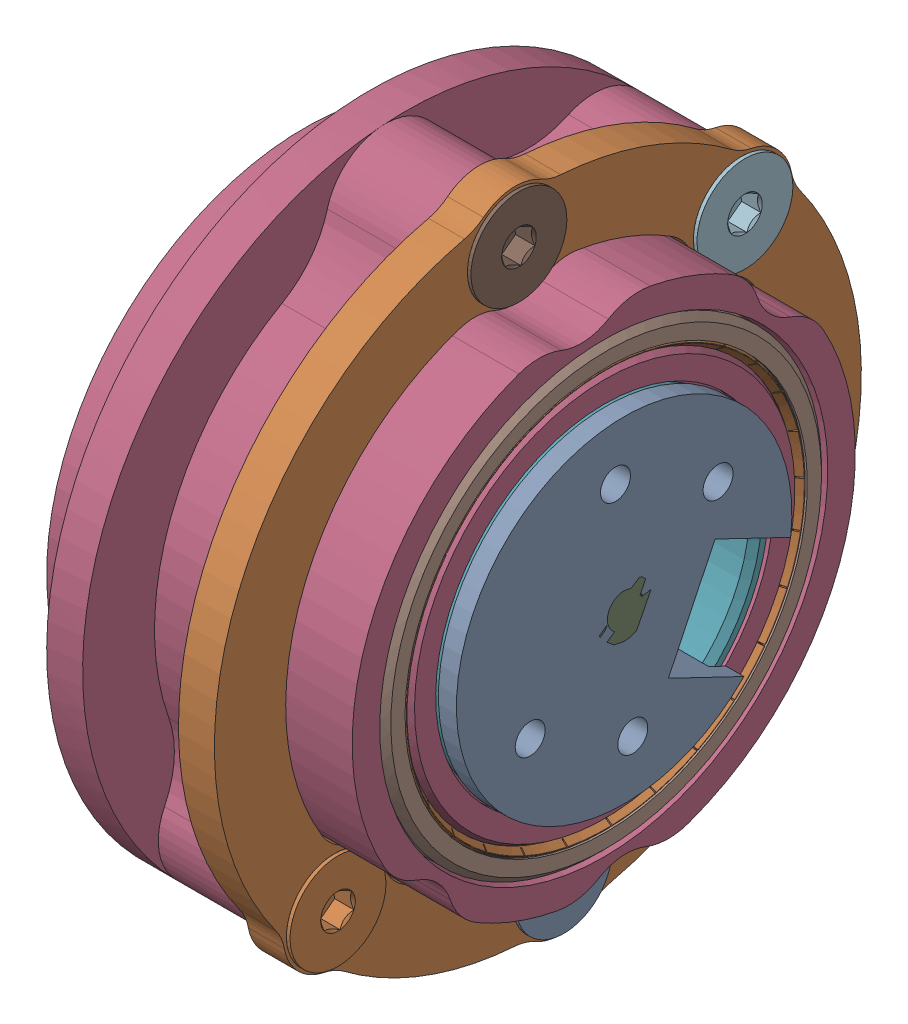
SolidWorks assembly 2808MH1-assem, configuration Default. Lengths in mm.
Overall size (28.51 69.48 69.48).
13 component instances, 9 part files, 27 mates.
Components (placement in the parent):
- 2808MH1-capThread-1: 2808MH1-capThread [Default] x (1 0 0) z (0 -0.432699 -0.901539) size (9.35 28 27.26)
- 2808MH1-clamp-1: 2808MH1-clamp [Default] at (-0.2 0 0) x (1 0 0) z (0 0.349734 0.936849) size (3 54 54)
- 2808MH1-shaft-1: 2808MH1-shaft [Default] x (1 0 0) z (0 0.432699 0.901539) size (13.15 15 15)
- 2808MH1-shell-1: 2808MH1-shell [Default] at (-0.2 0 0) x (1 0 0) z (0 0.349734 0.936849) size (25 54 54)
- 25mmID_37mmOD_7mmDepth_UnflangedRadialBearing-1: 25mmID_37mmOD_7mmDepth_UnflangedRadialBearing [5972K158] at (-9 0 0) x (0 0 -1) z (1 0 0) size (37 37 7)
- 25mmID_37mmOD_7mmDepth_UnflangedRadialBearing-2: 25mmID_37mmOD_7mmDepth_UnflangedRadialBearing [5972K158] at (9 0 0) x (0 0.030175 -0.999545) z (1 0 0) size (37 37 7)
- 8mmShaft_M6_16mmL_ShortThreadShoulderScrew-1: 8mmShaft_M6_16mmL_ShortThreadShoulderScrew [94361A535] x (0 0.716728 0.697353) z (-1 0 0) size (13 13 28.51)
- 2808MH-stator-1: 2808MH-stator [Default] at (-4.15 0 0) x (1 0 0) z (0 -0.460069 0.887883) size (12 28 28)
- M4x0.7_10mm_FHCS-1: M4x0.7_10mm_FHCS [91294A190] at (2.1 23.7506 1.8813) x (0 0.120954 -0.992658) z (1 0 0) size (8 8 10.14)
- M4x0.7_10mm_FHCS-2: M4x0.7_10mm_FHCS [91294A190] at (2.1 16.7078 -16.9847) x (0 0.120954 -0.992658) z (1 0 0) size (8 8 10.14)
- M4x0.7_10mm_FHCS-3: M4x0.7_10mm_FHCS [91294A190] at (2.1 -23.7506 -1.8813) x (0 0.120954 -0.992658) z (1 0 0) size (8 8 10.14)
- M4x0.7_10mm_FHCS-4: M4x0.7_10mm_FHCS [91294A190] at (2.1 -16.7078 16.9847) x (0 0.120954 -0.992658) z (1 0 0) size (8 8 10.14)
- 2808MH1-capHead-1: 2808MH1-capHead [Default] x (1 0 0) z (0 0.432699 0.901539) size (8.5 28 28)
Mates (geometry in assembly coordinates):
- Concentric1: concentric anti-aligned: cylinder of 2808MH1-capHead-1 through (-22.071 0 0) axis (-1 0 0) radius 4; cylinder of 8mmShaft_M6_16mmL_ShortThreadShoulderScrew-1 through (14 0 0) axis (1 0 0) radius 4
- Coincident1: coincident anti-aligned: plane of 2808MH1-capHead-1 through (-8.5 5.86 -2.8125) normal (-1 0 0); plane of 8mmShaft_M6_16mmL_ShortThreadShoulderScrew-1 through (-8.5 4.3424 -4.4631) normal (1 0 0)
- Concentric3: concentric anti-aligned: cylinder of 2808MH1-capThread-1 through (-22.071 0 0) axis (-1 0 0) radius 4; cylinder of 8mmShaft_M6_16mmL_ShortThreadShoulderScrew-1 through (14 0 0) axis (1 0 0) radius 4
- Concentric4: concentric anti-aligned: cylinder of 2808MH1-capHead-1 through (-22.071 0 0) axis (-1 0 0) radius 12.5; cylinder of 25mmID_37mmOD_7mmDepth_UnflangedRadialBearing-1 through (-5.5 0 0) axis (1 0 0) radius 12.5
- Coincident6: coincident anti-aligned: plane of 2808MH1-capHead-1 through (-12.5 11.2692 -5.4087) normal (1 0 0); plane of 25mmID_37mmOD_7mmDepth_UnflangedRadialBearing-1 through (-12.5 13.025 0) normal (-1 0 0)
- Concentric5: concentric anti-aligned: cylinder of 2808MH1-capThread-1 through (-22.071 0 0) axis (-1 0 0) radius 12.5; cylinder of 25mmID_37mmOD_7mmDepth_UnflangedRadialBearing-2 through (12.5 0 0) axis (1 0 0) radius 12.5
- Coincident7: coincident anti-aligned: plane of 2808MH1-capThread-1 through (12.5 -11.2692 5.4087) normal (-1 0 0); plane of 25mmID_37mmOD_7mmDepth_UnflangedRadialBearing-2 through (12.5 13.0191 0.393) normal (1 0 0)
- Concentric6: concentric anti-aligned: cylinder of 2808MH1-shell-1 through (-22.271 0 0) axis (-1 0 0) radius 18.7; cylinder of 25mmID_37mmOD_7mmDepth_UnflangedRadialBearing-1 through (-5.5 0 0) axis (1 0 0) radius 18.5
- Coincident8: coincident anti-aligned: plane of 2808MH1-shell-1 through (-5.5 14.2401 -5.316) normal (-1 0 0); plane of 25mmID_37mmOD_7mmDepth_UnflangedRadialBearing-1 through (-5.5 17.975 0) normal (1 0 0)
- Concentric7: concentric aligned: cylinder of 2808MH1-clamp-1 through (-22.271 0 0) axis (-1 0 0) radius 21.05; cylinder of 2808MH1-shell-1 through (-22.271 0 0) axis (-1 0 0) radius 21
- Distance1: distance = 8 mm anti-aligned: plane of 2808MH1-clamp-1 through (3.8 19.7207 -7.3619) normal (-1 0 0); plane of 2808MH1-shell-1 through (-4.2 25.2949 -9.4428) normal (1 0 0)
- Concentric8: concentric aligned: cylinder of 2808MH1-clamp-1 through (6.8 23.7506 1.8813) axis (1 0 0) radius 2.15; cylinder of 2808MH1-shell-1 through (3.3 23.7506 1.8813) axis (1 0 0) radius 1.65
- Distance2: distance = 0 mm: cylinder of 2808MH1-shaft-1 through (-22.071 0 0) axis (-1 0 0) radius 6.5
- Distance3: distance = 0 mm: cylinder of assembly; plane of assembly; cylinder of 2808MH1-shaft-1 through (-22.071 0 0) axis (-1 0 0) radius 6.5
- Symmetric1: symmetric aligned: plane of 2808MH1-capThread-1 through (14 -12.6215 6.0578) normal (1 0 0); plane of 2808MH1-capHead-1 through (-14 12.6215 -6.0578) normal (-1 0 0)
- Concentric10: concentric anti-aligned: cylinder of 2808MH1-clamp-1 through (6.8 23.7506 1.8813) axis (1 0 0) radius 2.15; cylinder of M4x0.7_10mm_FHCS-1 through (-2.9 23.7506 1.8813) axis (-1 0 0) radius 2
- Coincident13: coincident anti-aligned: circle of 2808MH1-clamp-1; circle of M4x0.7_10mm_FHCS-1
- Coincident14: coincident aligned: cone of 2808MH1-clamp-1 through (6.8 16.7078 -16.9847) axis (-1 0 0); circle of M4x0.7_10mm_FHCS-2
- Coincident15: coincident anti-aligned: circle of 2808MH1-clamp-1; circle of M4x0.7_10mm_FHCS-3
- Coincident16: coincident anti-aligned: circle of 2808MH1-clamp-1; circle of M4x0.7_10mm_FHCS-4
- Coincident18: coincident anti-aligned: plane of 2808MH1-shaft-1 through (-5.5 -4.9213 -27.5868) normal (-1 0 0); plane of 2808MH1-capHead-1 through (-5.5 3.6062 -1.7308) normal (1 0 0)
- Concentric11: concentric anti-aligned: cylinder of 2808MH1-shaft-1 through (-22.071 0 0) axis (-1 0 0) radius 6.5; cylinder of 8mmShaft_M6_16mmL_ShortThreadShoulderScrew-1 through (14 0 0) axis (1 0 0) radius 4
- Coincident19: coincident anti-aligned: plane of 2808MH1-shaft-1 through (-7 -8.8205 -25.7154) normal (0 0.901539 -0.432699); plane of 2808MH1-capHead-1 through (36.361 8.7623 10.9189) normal (0 -0.901539 0.432699)
- Tangent3: tangent aligned: cylinder of 2808MH1-shaft-1 through (-22.071 0 0) axis (-1 0 0) radius 6.5; cylinder of 2808MH-stator-1 through (-12.983 0 0) axis (-1 0 0) radius 6.5
- Coincident20: coincident anti-aligned: plane of 2808MH1-shaft-1 through (-4.15 5.86 -2.8125) normal (1 0 0); plane of 2808MH-stator-1 through (-4.15 6.6591 3.4505) normal (-1 0 0)
- Coincident21: coincident anti-aligned: plane of 2808MH1-capThread-1 through (4.65 -3.6062 1.7308) normal (-1 0 0); plane of 2808MH1-shaft-1 through (4.65 -5.8229 -27.1541) normal (1 0 0)
- Coincident22: coincident anti-aligned: plane of 2808MH1-capThread-1 through (36.361 -8.7623 -10.9189) normal (0 0.901539 -0.432699); plane of 2808MH1-shaft-1 through (6.15 -14.5452 -22.9677) normal (0 -0.901539 0.432699)
